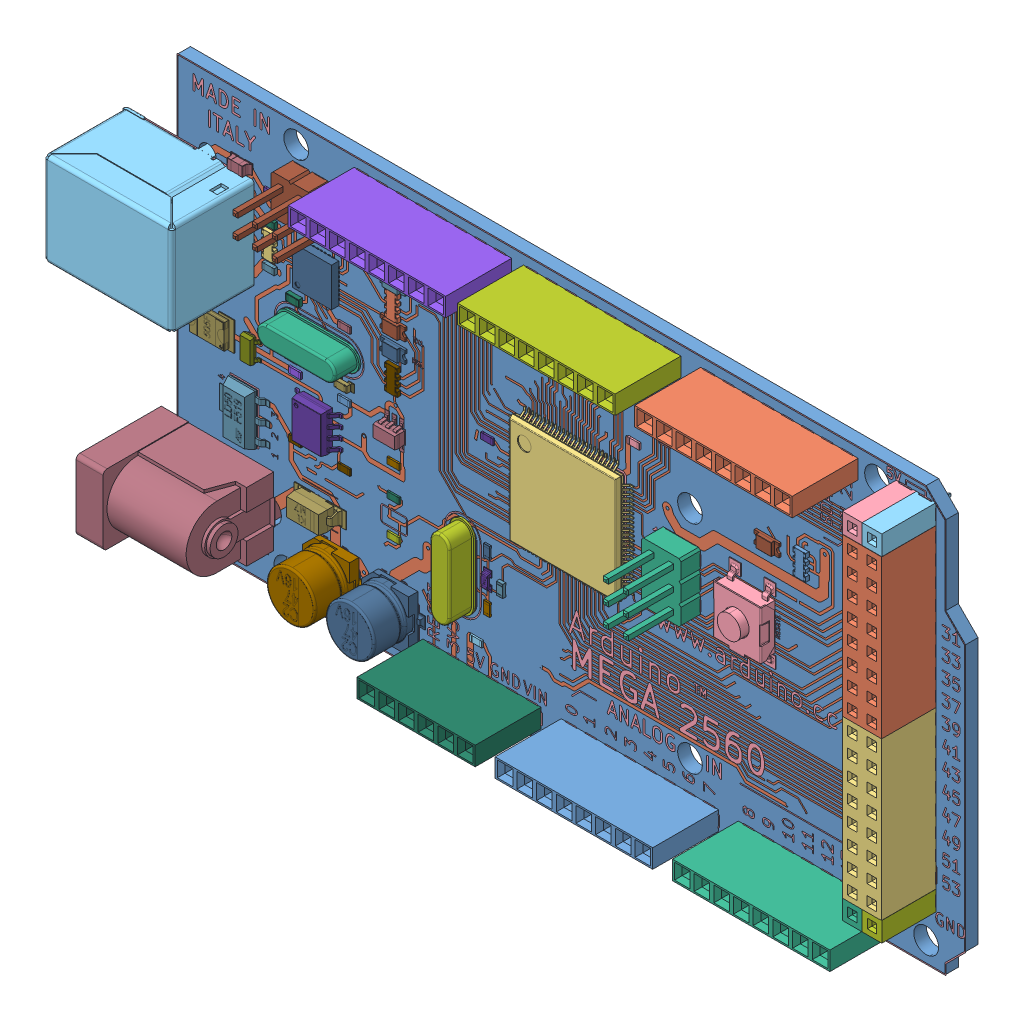
SolidWorks assembly Arduino_Mega_2560, configuration Default. Lengths in mm.
Overall size (108.38 53.5 15.58).
73 component instances, 69 part files, 0 mates.
Components (placement in the parent):
- Arduino_Mega_2560.step-1: Arduino_Mega_2560.step [Default] at origin size (108.38 53.5 15.58)
  - Board_Geoms.step-1: Board_Geoms.step [Default] at origin size (108.15 53.5 3.61)
    - Pcb.step-1: Pcb.step [Default] at (-148.5011 105.0036 0) size (101.6 53.34 1.6)
    - topTracks.step-1: topTracks.step [Default] at (-148.5011 105.0036 0.01) size (99.64 50.09 0.06)
    - botTracks.step-1: botTracks.step [Default] at (-148.5011 105.0036 -1.61) size (99 50 3.44)
    - topSilks.step-1: topSilks.step [Default] at (-148.5011 105.0036 0.07) size (108.15 53.5 0.39)
  - Step_Models.step-1: Step_Models.step [Default] at origin size (104.49 50.73 15.58)
    - Top.step-1: Top.step [Default] at origin size (104.49 50.73 15.58)
      - X2_USB_type_b_5C806054.step-1: X2_USB_type_b_5C806054.step [Default] at (-57.49 11.43 0) x (0 -1 0) z (-1 0 0) size (13.72 15.2 16.51)
      - ICSP2_PinHeader_2x03_P254mm_Vertical_5C805C79.step-1: ICSP2_PinHeader_2x03_P254mm_Vertical_5C805C79.step [Default] at (15.347 -1.23 0) x (-1 0 0) z (0 0 1) size (5.08 7.62 11.54)
      - PWML1_8_PORT_HEADER_5C805C9E.step-1: PWML1_8_PORT_HEADER_5C805C9E.step [Default] at (12.81 24.13 0) x (-1 0 0) z (0 0 1) size (20.32 2.41 10.51)
      - PWMH1_8_PORT_HEADER_5C805CEA.step-1: PWMH1_8_PORT_HEADER_5C805CEA.step [Default] at (-9.034 24.13 0) x (-1 0 0) z (0 0 1) size (20.32 2.41 10.51)
      - PC1__47uf_CAP_Dcase_cp_5C805D36.step-1: PC1__47uf_CAP_Dcase_cp_5C805D36.step [Default] at (-30.48 -20.955 0) x (0 1 0) z (0 0 1) size (6.6 8 5.82)
      - PC2__47uf_CAP_Dcase_cp_5C805D50.step-1: PC2__47uf_CAP_Dcase_cp_5C805D50.step [Default] at (-22.86 -20.955 0) x (0 1 0) z (0 0 1) size (6.6 8 5.82)
      - ON1_LED-WR-1206-GREEN_5C805D6A.step-1: ON1_LED-WR-1206-GREEN_5C805D6A.step [Default] at (25.4 10.16 0) x (-1 0 0) z (0 0 1) size (3.2 1.6 0.68)
      - D1_m7_diode_5C805D76.step-1: D1_m7_diode_5C805D76.step [Default] at (-32.385 -14.605 0) size (6.66 2.5 2.35)
      - X1_Power_jack_5C805D85.step-1: X1_Power_jack_5C805D85.step [Default] at (-52.966 -18.288 0) x (0 -1 0) z (0 0 1) size (11.2 15.9 15.35)
      - IC1_Circuit_integre_LD50_5C805DB9.step-1: IC1_Circuit_integre_LD50_5C805DB9.step [Default] at (-42.164 -8.89 0.25) x (0 -1 0) z (0 0 1) size (6.5 8.01 1.7)
      - POWER1_6_PORT_HEADER_5C805DD0.step-1: POWER1_6_PORT_HEADER_5C805DD0.step [Default] at (-17.93 -24.13 0) size (15.24 2.41 10.51)
      - C3_CAPA-0603_5C805E0A[2].step-1: C3_CAPA-0603_5C805E0A[2].step [Default] at (-22.86 17.78 0) size (1.6 0.8 0.45)
      - C6_CAPA-0603_5C805E18.step-1: C6_CAPA-0603_5C805E18.step [Default] at (-10.755 3.749 0) x (-1 0 0) z (0 0 1) size (1.6 0.8 0.45)
      - C2_CAPA-0603_5C805E26.step-1: C2_CAPA-0603_5C805E26.step [Default] at (-35.56 -8.89 0) size (1.6 0.8 0.45)
      - ADCL1_8_PORT_HEADER_5C805E34.step-1: ADCL1_8_PORT_HEADER_5C805E34.step [Default] at (-0.11 -24.13 0) size (20.32 2.41 10.51)
      - COM_8_PORT_HEADER_5C805E80.step-1: COM_8_PORT_HEADER_5C805E80.step [Default] at (35.67 24.13 0) x (-1 0 0) z (0 0 1) size (20.32 2.41 10.51)
      - IC3_ATMEGA2560-16AU_5C805ECC.step-1: IC3_ATMEGA2560-16AU_5C805ECC.step [Default] at (0 1.6764 0) size (16 16 1.2)
      - C5_CAPA-0603_5C805FAA.step-1: C5_CAPA-0603_5C805FAA.step [Default] at (8.128 12.7 0) size (1.6 0.8 0.45)
      - C4_CAPA-0603_5C805FB8.step-1: C4_CAPA-0603_5C805FB8.step [Default] at (-12.192 -19.558 0) size (1.6 0.8 0.45)
      - ADCH1_8_PORT_HEADER_5C805FC6.step-1: ADCH1_8_PORT_HEADER_5C805FC6.step [Default] at (22.75 -24.13 0) size (20.32 2.41 10.51)
      - C1_CAPA-0603_5C806012.step-1: C1_CAPA-0603_5C806012.step [Default] at (-22.86 -13.335 0) x (-1 0 0) z (0 0 1) size (1.6 0.8 0.45)
      - C8_CAPA-0603_5C806020.step-1: C8_CAPA-0603_5C806020.step [Default] at (-35.56 -1.27 0) size (1.6 0.8 0.45)
      - C13_CAPA-0603_5C80602E.step-1: C13_CAPA-0603_5C80602E.step [Default] at (-22.86 -5.08 0) size (1.6 0.8 0.45)
      - RX1_LED-WR-1206-Yellow_5C80603C.step-1: RX1_LED-WR-1206-Yellow_5C80603C.step [Default] at (-22.86 7.62 0) size (3.2 1.6 0.68)
      - TX1_LED-WR-1206-Yellow_5C806048.step-1: TX1_LED-WR-1206-Yellow_5C806048.step [Default] at (-22.86 10.16 0) size (3.2 1.6 0.68)
      - F1_Fusible_rearmable_mf-msmf050-2_5C806061.step-1: F1_Fusible_rearmable_mf-msmf050-2_5C806061.step [Default] at (-46.355 -1.27 0) x (-1 0 0) z (0 0 1) size (5.75 3.7 0.81)
      - C9_CAPA-0603_5C80606A.step-1: C9_CAPA-0603_5C80606A.step [Default] at (-29.21 6.985 0) size (1.6 0.8 0.45)
      - L2_LED-WR-1206-Yellow_5C806078.step-1: L2_LED-WR-1206-Yellow_5C806078.step [Default] at (-22.86 15.24 0) size (3.2 1.6 0.68)
      - C7_CAPA-0603_5C806084.step-1: C7_CAPA-0603_5C806084.step [Default] at (-22.86 -8.89 0) size (1.6 0.8 0.45)
      - T2_Semiconducteur_Fairchild_5C806092.step-1: T2_Semiconducteur_Fairchild_5C806092.step [Default] at (-41.275 -1.27 0.4) size (3.2 3 1.05)
      - IC5_LMH6658MA_NOPB_5C80609F.step-1: IC5_LMH6658MA_NOPB_5C80609F.step [Default] at (-32.512 -5.08 0) size (6 4.9 1.75)
      - C12_CAPA-0603_5C8060B9.step-1: C12_CAPA-0603_5C8060B9.step [Default] at (-29.21 -8.89 0) x (-1 0 0) z (0 0 1) size (1.6 0.8 0.45)
      - C11_CAPA-0603_5C8060C7.step-1: C11_CAPA-0603_5C8060C7.step [Default] at (-29.21 -1.27 0) size (1.6 0.8 0.45)
      - XIOH1_PinSocket_2x08_P254mm_Vertical_5C8060D5.step-1: XIOH1_PinSocket_2x08_P254mm_Vertical_5C8060D5.step [Default] at (45.7 21.55 0) size (5.08 20.32 10.1)
      - XIOL1_PinSocket_2x08_P254mm_Vertical_5C806131.step-1: XIOL1_PinSocket_2x08_P254mm_Vertical_5C806131.step [Default] at (45.7 1.23 0) size (5.08 20.32 10.1)
      - JP1_PinSocket_1x01_P254mm_Vertical_5C80618D.step-1: JP1_PinSocket_1x01_P254mm_Vertical_5C80618D.step [Default] at (43.18 24.13 0) size (2.54 2.54 10.1)
      - JP2_PinSocket_1x01_P254mm_Vertical_5C80619A.step-1: JP2_PinSocket_1x01_P254mm_Vertical_5C80619A.step [Default] at (45.72 24.13 0) size (2.54 2.54 10.1)
      - JP3_PinSocket_1x01_P254mm_Vertical_5C8061A7.step-1: JP3_PinSocket_1x01_P254mm_Vertical_5C8061A7.step [Default] at (43.18 -19.05 0) size (2.54 2.54 10.1)
      - JP4_PinSocket_1x01_P254mm_Vertical_5C8061B4.step-1: JP4_PinSocket_1x01_P254mm_Vertical_5C8061B4.step [Default] at (45.72 -19.05 0) size (2.54 2.54 10.1)
      - C10_CAPA-0603_5C8061D3.step-1: C10_CAPA-0603_5C8061D3.step [Default] at (-38.735 17.145 0) x (-1 0 0) z (0 0 1) size (1.6 0.8 0.45)
      - IC4_atmega16u2_5C8061E1.step-1: IC4_atmega16u2_5C8061E1.step [Default] at (-32.512 11.43 0) x (0 1 0) z (0 0 1) size (5.1 5.1 1)
      - IC4_ATMEGA16U2_5C8061E1[2].step-1: IC4_ATMEGA16U2_5C8061E1[2].step [Default] at (-32.512 11.43 0) x (0 1 0) z (0 0 1) size (5.1 5.1 1)
      - ICSP1_PinHeader_2x03_P254mm_Vertical_5C806266.step-1: ICSP1_PinHeader_2x03_P254mm_Vertical_5C806266.step [Default] at (-35.012 18.308 0) x (0 1 0) z (0 0 1) size (5.08 7.62 11.54)
      - Y2_Quartz_16MHz_5C80628B.step-1: Y2_Quartz_16MHz_5C80628B.step [Default] at (-32.512 3.81 0) x (-1 0 0) z (0 0 1) size (3.4 2 0.8)
      - L1_blm21_5C8062A9.step-1: L1_blm21_5C8062A9.step [Default] at (-42.545 18.542 0) x (-1 0 0) z (0 0 1) size (2.78 1.32 0.95)
      - Z1_VARISTOR_CG0603MLC-05E_5C8062B5.step-1: Z1_VARISTOR_CG0603MLC-05E_5C8062B5.step [Default] at (-38.735 8.89 0) size (1.6 0.8 0.45)
      - Z2_VARISTOR_CG0603MLC-05E_5C8062C0.step-1: Z2_VARISTOR_CG0603MLC-05E_5C8062C0.step [Default] at (-38.735 13.97 0) size (1.6 0.8 0.45)
      - Y1_Quartz_16MHz_5C8062DD.step-1: Y1_Quartz_16MHz_5C8062DD.step [Default] at (-13.97 -12.065 0) x (0 -1 0) z (0 0 1) size (3.4 2 0.8)
      - R1_Resistance_105_5C8062E9.step-1: R1_Resistance_105_5C8062E9.step [Default] at (-10.795 -12.065 0) x (0 1 0) z (0 0 1) size (2.4 1 0.5)
      - RN4_R_Array_Convex_4x0603_5C8062F7.step-1: RN4_R_Array_Convex_4x0603_5C8062F7.step [Default] at (-22.86 4.445 0) size (1.6 3.2 0.5)
      - RN1_R_Array_Convex_4x0603_5C806331.step-1: RN1_R_Array_Convex_4x0603_5C806331.step [Default] at (29.845 10.16 0) x (-1 0 0) z (0 0 1) size (1.6 3.2 0.5)
      - RN3_R_Array_Convex_4x0603_5C806350.step-1: RN3_R_Array_Convex_4x0603_5C806350.step [Default] at (-22.86 12.7 0) x (-1 0 0) z (0 0 1) size (1.6 3.2 0.5)
      - RN2_R_Array_Convex_4x0603_5C806371.step-1: RN2_R_Array_Convex_4x0603_5C806371.step [Default] at (-38.735 11.43 0) size (1.6 3.2 0.5)
      - RESET1_RESET_BUTTON_5C80638C.step-1: RESET1_RESET_BUTTON_5C80638C.step [Default] at (23.368 1.27 0) size (6.2 9.6 3.1)
      - R2_Resistance_105_5C8063AC.step-1: R2_Resistance_105_5C8063AC.step [Default] at (-32.385 0.635 0) size (2.4 1 0.5)
      - Q1_A68B7E88-986F-45B9-BD79-59358D84B993_5C8063BA.step-1: Q1_A68B7E88-986F-45B9-BD79-59358D84B993_5C8063BA.step [Default] at (-30.012 3.81 0) x (-1 0 0) z (0 0 1) size (10.67 3.05 5.63)
      - Q2_A68B7E88-986F-45B9-BD79-59358D84B993_5C8063C7.step-1: Q2_A68B7E88-986F-45B9-BD79-59358D84B993_5C8063C7.step [Default] at (-13.97 -9.565 0) x (0 -1 0) z (0 0 1) size (10.67 3.05 5.63)
      - C14_CAPA-0603_5C8063D4.step-1: C14_CAPA-0603_5C8063D4.step [Default] at (-10.795 -15.24 0) x (0 1 0) z (0 0 1) size (1.6 0.8 0.45)
      - C14_CAPA-0603_5C8063D4[2].step-1: C14_CAPA-0603_5C8063D4[2].step [Default] at (-10.795 -15.24 0) x (0 1 0) z (0 0 1) size (1.6 0.8 0.45)
      - C15_CAPA-0603_5C8063E2.step-1: C15_CAPA-0603_5C8063E2.step [Default] at (-10.795 -8.89 0) x (0 -1 0) z (0 0 1) size (1.6 0.8 0.45)
      - C16_Condensateur_MLC_5C8063F0.step-1: C16_Condensateur_MLC_5C8063F0.step [Default] at (-35.56 0.635 0) x (-1 0 0) z (0 0 1) size (2.4 1 0.7)
      - C17_Condensateur_MLC_5C8063FE.step-1: C17_Condensateur_MLC_5C8063FE.step [Default] at (-29.21 0.635 0) size (2.4 1 0.7)
      - IC6_lmv358_5C80640C.step-1: IC6_lmv358_5C80640C.step [Default] at (-22.86 -1.4986 0) x (0 -1 0) z (0 0 1) size (3.7 2.9 1.4)
      - R3_R_0603_1608Metric_5C806424.step-1: R3_R_0603_1608Metric_5C806424.step [Default] at (-8.89 -12.065 0) x (0 -1 0) z (0 0 1) size (1.6 0.8 0.45)
      - R4_RESC-0603_5C806432.step-1: R4_RESC-0603_5C806432.step [Default] at (-35.56 6.985 0) x (-1 0 0) z (0 0 1) size (1.7 0.9 0.55)
